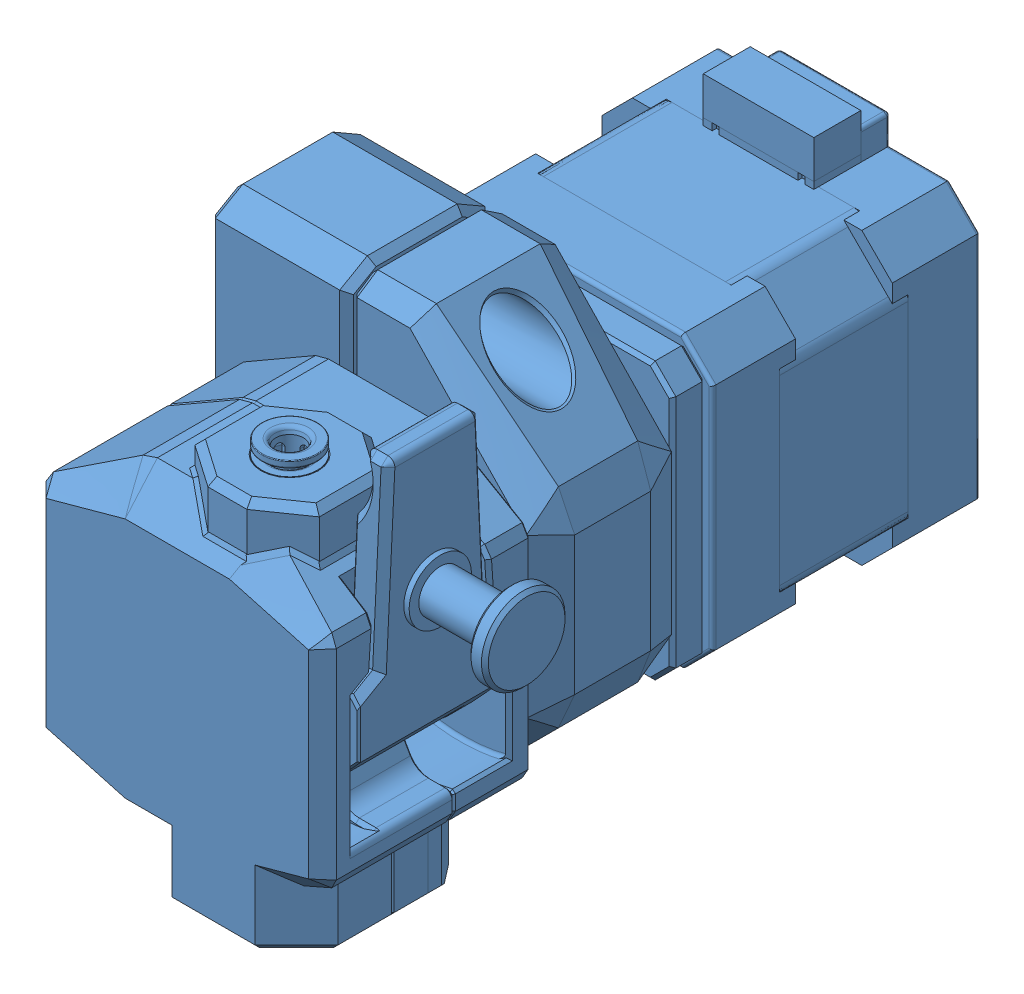
SolidWorks assembly BondtechQR, configuration Default. Lengths in mm.
Overall size (67.5 63 96.15).
5 component instances, 3 part files, 13 mates.
Components (placement in the parent):
- BondtechQR-1: BondtechQR [Default] at origin size (60.8 63 96.15)
- Tee Nut-1: Tee Nut [Default] at (-26.8 10 55.65) x (0 1 0) z (-1 0 0) size (15 10 3)
- Low Profile Screw M5-1: Low Profile Screw M5 [M5 x 10] at (-31.7 10 55.65) x (-1 0 0) z (0 -0.924225 -0.381849) size (11.62 9 9)
- Low Profile Screw M5-2: Low Profile Screw M5 [M5 x 10] at (-31.7 -10 55.65) x (-1 0 0) z (0 -0.85199 -0.523557) size (11.62 9 9)
- Tee Nut-2: Tee Nut [Default] at (-26.8 -10 55.65) x (0 1 0) z (-1 0 0) size (15 10 3)
Mates (geometry in assembly coordinates):
- Coincident1: coincident aligned: plane of BondtechQR-1 through (0 0 0) normal (0 0 1); plane of assembly through (0 0 0) normal (0 0 1)
- Coincident2: coincident aligned: plane of BondtechQR-1 through (0 0 0) normal (0 1 0); plane of assembly through (0 0 0) normal (0 1 0)
- Coincident3: coincident aligned: plane of BondtechQR-1 through (0 0 0) normal (1 0 0); plane of assembly through (0 0 0) normal (1 0 0)
- Concentric1: concentric aligned: cylinder of BondtechQR-1 through (-9.8 10 55.65) axis (-1 0 0) radius 2.75; cylinder of Low Profile Screw M5-1 through (-21.7 10 55.65) axis (-1 0 0) radius 2.5
- Coincident4: coincident aligned: circle of BondtechQR-1; plane of Low Profile Screw M5-1 through (-21.7 11.589 51.8039) normal (-1 0 0)
- Concentric2: concentric aligned: cylinder of Tee Nut-1 through (-29.8 10 55.65) axis (-1 0 0) radius 2.1; cylinder of Low Profile Screw M5-1 through (-21.7 10 55.65) axis (-1 0 0) radius 2.5
- Parallel1: parallel aligned: plane of BondtechQR-1 through (0 0 44.65) normal (0 0 -1); plane of Tee Nut-1 through (-28.4 7 50.65) normal (0 0 -1)
- Distance1: distance = 1.8 mm anti-aligned: plane of BondtechQR-1 through (-25 0 44.65) normal (-1 0 0); plane of Tee Nut-1 through (-26.8 16 52.65) normal (1 0 0)
- Concentric3: concentric aligned: cylinder of Low Profile Screw M5-2 through (-21.7 -10 55.65) axis (-1 0 0) radius 2.5; cylinder of Tee Nut-2 through (-29.8 -10 55.65) axis (-1 0 0) radius 2.1
- Concentric4: concentric aligned: cylinder of BondtechQR-1 through (-9.8 -10 55.65) axis (-1 0 0) radius 2.75; cylinder of Low Profile Screw M5-2 through (-21.7 -10 55.65) axis (-1 0 0) radius 2.5
- Coincident7: coincident aligned: circle of BondtechQR-1; plane of Low Profile Screw M5-2 through (-21.7 -7.8212 52.1045) normal (-1 0 0)
- Parallel2: parallel aligned: plane of BondtechQR-1 through (0 0 44.65) normal (0 0 -1); plane of Tee Nut-2 through (-28.4 -13 50.65) normal (0 0 -1)
- Distance2: distance = 1.8 mm anti-aligned: plane of BondtechQR-1 through (-25 0 44.65) normal (-1 0 0); plane of Tee Nut-2 through (-26.8 -4 52.65) normal (1 0 0)
